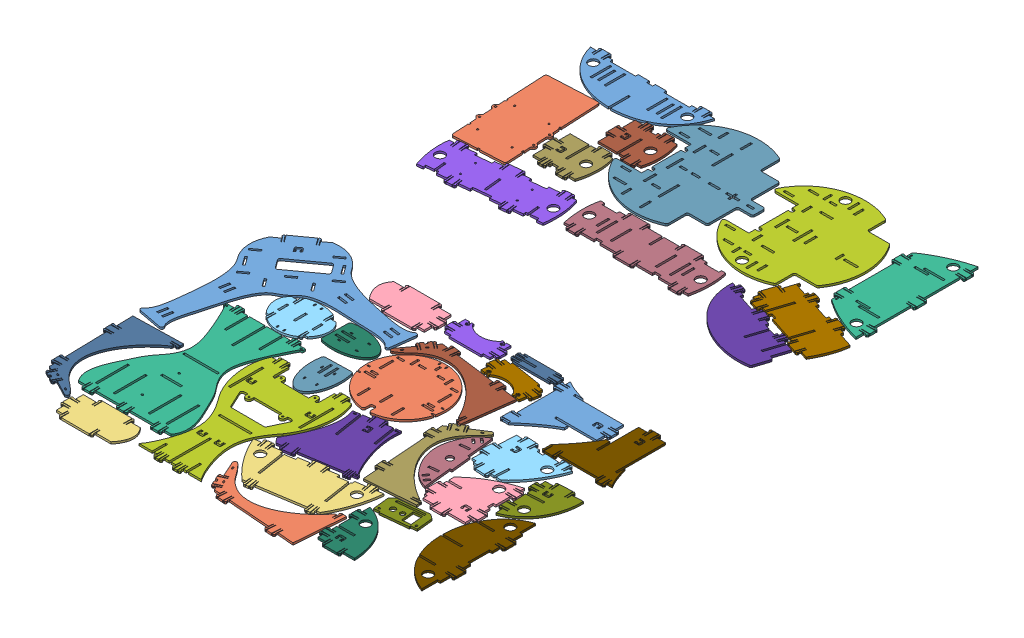
SolidWorks assembly frame-laser, configuration Default. Lengths in mm.
Overall size (686.62 156.13 900).
39 component instances, 39 part files, 42 mates.
Components (placement in the parent):
- frame-1-1-1: frame-1-1 [Default] at (74.1729 -23 -375.7391) x (0.809017 0 -0.587785) z (0.587785 0 0.809017) size (295.79 3.1 186.32)
- frame-1-10-1: frame-1-10 [Default] at (456.9815 12.5145 -4.773) x (0.723244 0.688233 0.057043) z (-0.686102 0.72549 -0.054113) size (113.31 80 107.71)
- frame-1-2-1: frame-1-2 [Default] at (50.8522 -54 -28.7315) x (0 -1 0) z (-0.002751 0 0.999996) size (3.01 97.8 52)
- frame-1-3-1: frame-1-3 [Default] at (267.6408 -54 -405.6592) x (0 1 0) z (0 0 1) size (3.01 97.8 52)
- frame-1-4-1: frame-1-4 [Default] at (135.627 -138 -310.2809) size (81.05 3.01 65.59)
- frame-1-5-1: frame-1-5 [Default] at (121.443 -6 -57.0487) x (1 0 0) z (0 1 0) size (149.92 222 3.01)
- frame-1-6-1: frame-1-6 [Default] at (225.6247 -40 -277.1128) x (0.999996 0 0.002751) z (0 -1 0) size (132.35 222 3.01)
- frame-1-7-1: frame-1-7 [Default] at (351.9945 -27.5 -410.1437) x (0 -1 0) z (0.002751 0 -0.999996) size (3 80 34)
- frame-1-8-1: frame-1-8 [Default] at (433.5583 -27.5 -416.2013) x (0 1 0) z (-0.159151 0 0.987254) size (3 80 34)
- frame-1-9-1: frame-1-9 [Default] at (-14.5876 -24.5145 -241.1141) x (-0.017118 -0.688233 -0.725288) z (0.016238 -0.72549 0.688041) size (113.31 80 107.71)
- Part38^frame-laser-1: Part38^frame-laser [Default] x (1 0 0) z (0 1 0) size (600 900 0) (virtual)
- frame-1-11-1: frame-1-11 [Default] at (442.8469 12.5145 -399.8849) x (-0.719299 -0.688233 -0.094575) z (-0.68236 0.72549 -0.089718) size (113.31 80 107.71)
- frame-1-12-1: frame-1-12 [Default] at (370.7955 -24.5145 -126.5265) x (-0.05481 0.688233 -0.723416) z (-0.051995 -0.72549 -0.686266) size (113.31 80 107.71)
- frame-1-13-1: frame-1-13 [Default] at (446.9436 -94 -258.5003) x (0.104528 0 0.994522) z (-0.994522 0 0.104528) size (113.29 3.01 38.9)
- frame-1-14-1: frame-1-14 [Default] at (240.7759 133.5216 -396.3883) x (0.678904 0.635631 -0.367509) z (0.733873 -0.602989 0.312785) size (55.67 57.08 56.23)
- frame-1-15-1: frame-1-15 [Default] at (77.1149 133.5216 -320.1217) x (0.367509 -0.635631 -0.678904) z (0.312785 -0.602989 0.733873) size (55.67 57.08 56.23)
- frame-1-16-1: frame-1-16 [Default] at (461.6625 -67 -184.7149) x (0.994806 0 -0.101792) z (0 -1 0) size (59.51 32 3.01)
- frame-1-17-1: frame-1-17 [Default] at (289.5059 -1.5 -384.2331) x (0 -1 0) z (-0.987688 0 0.156434) size (3.01 107 110.64)
- frame-1-18-1: frame-1-18 [Default] at (532.5712 -27 -575.1124) x (0 -1 0) z (-1 0 0) size (3.01 107 99.81)
- frame-1-19-1: frame-1-19 [Default] at (652.9353 -27 -391.7403) x (0 1 0) z (-0.002751 0 0.999996) size (3.01 107 99.81)
- frame-2-1-1: frame-2-1 [Default] at (304.5032 -236 -315.1911) size (118.54 3.01 117.87)
- frame-2-2-1: frame-2-2 [Default] at (388.2412 -34 150.9481) x (-0.988115 0 0.153717) z (0 -1 0) size (170.1 79 3.01)
- frame-2-3-1: frame-2-3 [Default] at (220.3902 -45 -193.6509) x (0 -1 0) z (0 0 1) size (3.01 79 94.28)
- frame-2-4-1: frame-2-4 [Default] at (440.6893 -45 -33.045) x (0 1 0) z (-0.998482 0 -0.055083) size (3.01 79 94.28)
- frame-2-5-1: frame-2-5 [Default] at (272.3715 -11.5 -805.883) x (0 0 1) z (0 1 0) size (181.75 79 3.01)
- frame-3-1-1: frame-3-1 [Default] at (406.1365 -306 -806.6525) x (0 0 -1) z (1 0 0) size (183.22 3.01 173.65)
- frame-3-2-1: frame-3-2 [Default] at (141.0558 -34 -315.9588) x (-0.994806 0 0.101792) z (0 -1 0) size (179.05 67 3.01)
- frame-3-3-1: frame-3-3 [Default] at (381.4658 -1.5 -389.8345) x (0 -1 0) z (0.951057 0 0.309017) size (3.01 67 132.76)
- frame-3-4-1: frame-3-4 [Default] at (711.1025 -55 -438.0689) x (0 0 -1) z (0 1 0) size (18 67 3)
- frame-3-5-1: frame-3-5 [Default] at (127.8462 -65 -1136.6668) x (0 -1 0) z (-1 0 0) size (3.01 67 73.27)
- frame-3-6-1: frame-3-6 [Default] at (95.9647 -65 -403.7853) x (0 1 0) z (-0.999996 0 -0.002751) size (3.01 67 73.27)
- frame-3-7-1: frame-3-7 [Default] at (302.2745 0 -339.8862) x (1 0 0) z (0 1 0) size (191.54 67 3.01)
- frame-4-1-1: frame-4-1 [Default] at (248.7392 -364 -804.4807) x (0 0 -1) z (1 0 0) size (186 3.01 176.58)
- frame-4-2-1: frame-4-2 [Default] at (68.5541 42 -53.5631) x (0 -1 0) z (0 0 1) size (3.01 60.42 83.5)
- frame-4-3-1: frame-4-3 [Default] at (166.1039 42 -282.6577) x (0 1 0) z (-0.049589 0 -0.99877) size (3.01 60.42 83.5)
- frame-4-4-1: frame-4-4 [Default] at (613.4731 -1.5 -1011.0332) x (0 -1 0) z (-0.951057 0 -0.309017) size (3.01 69.84 143.22)
- frame-4-5-1: frame-4-5 [Default] at (944.5602 -34 -150.8399) x (-0.002751 0 0.999996) z (0 -1 0) size (168.9 64.64 3.01)
- frame-4-6-1: frame-4-6 [Default] at (95.4347 0 -1255.6915) x (-1 0 0) z (0 1 0) size (184.45 69.82 3.01)
- frame-5-1-1: frame-5-1 [Default] at (31.8332 -48 -1066.6952) x (0.99877 0 -0.049589) z (0 -1 0) size (85 148.5 3)
Mates (geometry in assembly coordinates):
- InPlace1: in place: plane of Part38^frame-laser-1 through (0 0 0) normal (0 1 0); moOrthogonalPlaneRef_w of Part38^frame-laser-1 through (0 0 0) normal (0 0 -1); line of Part38^frame-laser-1 through (55 -55 0) axis (0 0 1); unknown of Part38^frame-laser-1
- Coincident7: coincident aligned: plane of Part38^frame-laser-1; plane of assembly
- Coincident8: coincident aligned: plane of Part38^frame-laser-1 through (0 0 0) normal (0 0 -1); moOrthogonalPlaneRef_w of assembly
- Coincident9: coincident anti-aligned: plane of Part38^frame-laser-1; moOrthogonalPlaneRef_w of assembly
- Coincident1: coincident aligned: plane of frame-1-3-1 through (267.6408 0 -405.6592) normal (0 1 0); plane of assembly through (0 0 0) normal (0 1 0)
- Coincident2: coincident aligned: plane of frame-1-4-1 through (135.627 0 -310.2809) normal (0 1 0); plane of assembly through (0 0 0) normal (0 1 0)
- Coincident3: coincident aligned: plane of frame-1-9-1 through (-14.5876 0 -241.1141) normal (0 1 0); plane of assembly through (0 0 0) normal (0 1 0)
- Coincident5: coincident aligned: plane of frame-1-6-1 through (225.6247 0 -277.1128) normal (0 1 0); plane of assembly through (0 0 0) normal (0 1 0)
- Coincident6: coincident aligned: plane of frame-1-10-1 through (456.9815 0 -4.773) normal (0 1 0); plane of assembly through (0 0 0) normal (0 1 0)
- Coincident7: coincident aligned: plane of frame-1-5-1 through (121.443 0 -57.0487) normal (0 1 0); plane of assembly through (0 0 0) normal (0 1 0)
- Coincident8: coincident aligned: plane of frame-1-1-1 through (74.1729 0 -375.7391) normal (0 1 0); plane of assembly through (0 0 0) normal (0 1 0)
- Coincident9: coincident aligned: plane of frame-1-2-1 through (50.8522 0 -28.7315) normal (0 1 0); plane of assembly through (0 0 0) normal (0 1 0)
- Coincident10: coincident aligned: plane of frame-1-11-1 through (442.8469 0 -399.8849) normal (0 1 0); plane of assembly through (0 0 0) normal (0 1 0)
- Coincident11: coincident aligned: plane of frame-1-7-1 through (351.9945 0 -410.1437) normal (0 1 0); plane of assembly through (0 0 0) normal (0 1 0)
- Coincident12: coincident aligned: plane of frame-1-8-1 through (433.5583 0 -416.2013) normal (0 1 0); plane of assembly through (0 0 0) normal (0 1 0)
- Coincident13: coincident aligned: plane of frame-1-12-1 through (370.7955 0 -126.5265) normal (0 1 0); plane of assembly through (0 0 0) normal (0 1 0)
- Coincident14: coincident aligned: plane of frame-1-13-1 through (405.3665 0 -267.3291) normal (0 1 0); plane of assembly through (0 0 0) normal (0 1 0)
- Coincident15: coincident aligned: plane of frame-2-2-1 through (388.2412 0 150.9481) normal (0 1 0); plane of assembly through (0 0 0) normal (0 1 0)
- Coincident16: coincident aligned: plane of frame-2-3-1 through (220.3902 0 -193.6509) normal (0 1 0); plane of assembly through (0 0 0) normal (0 1 0)
- Coincident17: coincident aligned: plane of frame-2-4-1 through (440.6893 0 -33.045) normal (0 1 0); plane of assembly through (0 0 0) normal (0 1 0)
- Coincident19: coincident aligned: plane of frame-1-17-1 through (289.5059 0 -384.2331) normal (0 1 0); plane of assembly through (0 0 0) normal (0 1 0)
- Coincident20: coincident aligned: plane of frame-1-19-1 through (652.9353 0 -391.7403) normal (0 1 0); plane of assembly through (0 0 0) normal (0 1 0)
- Coincident21: coincident aligned: plane of frame-1-18-1 through (532.5712 0 -575.1124) normal (0 1 0); plane of assembly through (0 0 0) normal (0 1 0)
- Coincident22: coincident aligned: plane of frame-1-15-1 through (242.3277 0 -334.3938) normal (0 1 0); plane of assembly through (0 0 0) normal (0 1 0)
- Coincident23: coincident aligned: plane of frame-1-14-1 through (226.5037 0 -231.1755) normal (0 1 0); plane of assembly through (0 0 0) normal (0 1 0)
- Coincident24: coincident aligned: plane of frame-2-1-1 through (245.2406 0 -315.3849) normal (0 1 0); plane of assembly through (0 0 0) normal (0 1 0)
- Coincident25: coincident aligned: plane of frame-3-4-1 through (711.1025 0 -438.0689) normal (0 1 0); plane of assembly through (0 0 0) normal (0 1 0)
- Coincident26: coincident aligned: plane of frame-1-16-1 through (431.4534 0 -114.6249) normal (0 1 0); plane of assembly through (0 0 0) normal (0 1 0)
- Coincident27: coincident aligned: plane of frame-2-5-1 through (272.3715 0 -805.883) normal (0 1 0); plane of assembly through (0 0 0) normal (0 1 0)
- Coincident28: coincident aligned: plane of frame-3-2-1 through (141.0558 0 -315.9588) normal (0 1 0); plane of assembly through (0 0 0) normal (0 1 0)
- Coincident29: coincident aligned: plane of frame-3-1-1 through (406.1395 0 -715.059) normal (0 1 0); plane of assembly through (0 0 0) normal (0 1 0)
- Coincident30: coincident aligned: plane of frame-4-6-1 through (95.4347 0 -1255.6915) normal (0 1 0); plane of assembly through (0 0 0) normal (0 1 0)
- Coincident31: coincident aligned: plane of frame-5-1-1 through (87.4434 0 -723.03) normal (0 1 0); plane of assembly through (0 0 0) normal (0 1 0)
- Coincident32: coincident aligned: plane of frame-3-7-1 through (302.2745 0 -339.8862) normal (0 1 0); plane of assembly through (0 0 0) normal (0 1 0)
- Coincident33: coincident aligned: plane of frame-4-1-1 through (248.6761 0 -711.5011) normal (0 1 0); plane of assembly through (0 0 0) normal (0 1 0)
- Coincident34: coincident aligned: plane of frame-4-5-1 through (944.5602 0 -150.8399) normal (0 1 0); plane of assembly through (0 0 0) normal (0 1 0)
- Coincident35: coincident aligned: plane of frame-4-4-1 through (613.4731 0 -1011.0332) normal (0 1 0); plane of assembly through (0 0 0) normal (0 1 0)
- Coincident36: coincident aligned: plane of frame-4-3-1 through (166.1039 0 -282.6577) normal (0 1 0); plane of assembly through (0 0 0) normal (0 1 0)
- Coincident37: coincident aligned: plane of frame-4-2-1 through (68.5541 0 -53.5631) normal (0 1 0); plane of assembly through (0 0 0) normal (0 1 0)
- Coincident38: coincident aligned: plane of frame-3-3-1 through (381.4658 0 -389.8345) normal (0 1 0); plane of assembly through (0 0 0) normal (0 1 0)
- Coincident39: coincident aligned: plane of frame-3-5-1 through (127.8462 0 -1136.6668) normal (0 1 0); plane of assembly through (0 0 0) normal (0 1 0)
- Coincident40: coincident aligned: plane of frame-3-6-1 through (95.9647 0 -403.7853) normal (0 1 0); plane of assembly through (0 0 0) normal (0 1 0)
